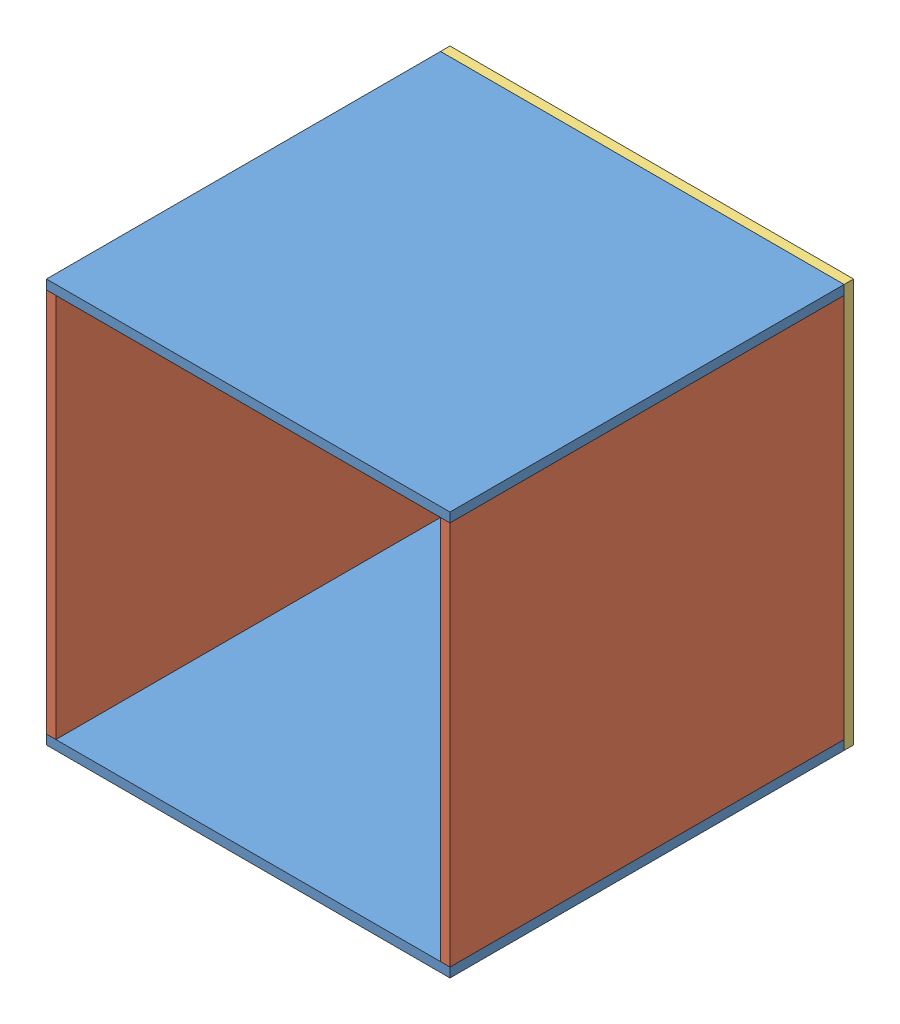
SolidWorks assembly Arm mount box, configuration Default. Lengths in mm.
Overall size (203.2 203.2 203.2).
5 component instances, 3 part files, 12 mates.
Components (placement in the parent):
- Upper Hub top and bottom PL-1: Upper Hub top and bottom PL [Default] at (-17.5452 -93.1073 -0.137) size (203.2 4.76 198.44)
- Upper Hub top and bottom PL-2: Upper Hub top and bottom PL [Default] at (-17.5452 105.3302 -0.137) size (203.2 4.76 198.44)
- Upper Hub side PL-1: Upper Hub side PL [Default] at (84.0548 8.4927 -0.137) x (0 0 1) z (-1 0 0) size (198.44 193.68 4.76)
- Upper Hub side PL-2: Upper Hub side PL [Default] at (-114.3827 8.4927 -0.137) x (0 0 1) z (-1 0 0) size (198.44 193.68 4.76)
- Upper hub PL-1: Upper hub PL [Default] at (-17.5452 8.4927 -104.1182) size (203.2 203.2 4.76)
Mates (geometry in assembly coordinates):
- Coincident11: coincident anti-aligned: plane of Upper Hub side PL-2 through (-119.1452 105.3302 -99.3557) normal (0 0 -1); plane of Upper hub PL-1 through (-119.1452 -93.1073 -99.3557) normal (0 0 1)
- Coincident12: coincident anti-aligned: plane of Upper Hub side PL-1 through (79.2923 110.0927 -99.3557) normal (0 0 -1); plane of Upper hub PL-1 through (-119.1452 -93.1073 -99.3557) normal (0 0 1)
- Coincident14: coincident aligned: plane of Upper Hub side PL-1 through (84.0548 -83.5823 -99.3557) normal (1 0 0); plane of Upper hub PL-1 through (84.0548 110.0927 -99.3557) normal (1 0 0)
- Coincident16: coincident aligned: plane of Upper Hub side PL-2 through (-119.1452 -88.3448 -99.3557) normal (-1 0 0); plane of Upper hub PL-1 through (-119.1452 110.0927 -99.3557) normal (-1 0 0)
- Coincident18: coincident aligned: plane of Upper Hub top and bottom PL-2 through (-119.1452 110.0927 -99.3557) normal (-1 0 0); plane of Upper hub PL-1 through (-119.1452 110.0927 -99.3557) normal (-1 0 0)
- Coincident21: coincident aligned: plane of Upper Hub top and bottom PL-1 through (-119.1452 -88.3448 -99.3557) normal (-1 0 0); plane of Upper Hub side PL-2 through (-119.1452 -88.3448 -99.3557) normal (-1 0 0)
- Coincident23: coincident aligned: plane of Upper Hub top and bottom PL-2 through (84.0548 110.0927 99.0818) normal (0 0 1); plane of Upper Hub side PL-2 through (-119.1452 105.3302 99.0818) normal (0 0 1)
- Coincident24: coincident aligned: plane of Upper Hub top and bottom PL-1 through (84.0548 -88.3448 99.0818) normal (0 0 1); plane of Upper Hub side PL-2 through (-119.1452 105.3302 99.0818) normal (0 0 1)
- Coincident25: coincident aligned: plane of Upper Hub top and bottom PL-1 through (-119.1452 -93.1073 99.0818) normal (0 -1 0); plane of Upper hub PL-1 through (84.0548 -93.1073 -99.3557) normal (0 -1 0)
- Coincident27: coincident aligned: plane of Upper Hub top and bottom PL-2 through (-119.1452 110.0927 99.0818) normal (0 1 0); plane of Upper hub PL-1 through (84.0548 110.0927 -99.3557) normal (0 1 0)
- Coincident28: coincident anti-aligned: plane of Upper Hub top and bottom PL-2 through (-119.1452 105.3302 99.0818) normal (0 -1 0); plane of Upper Hub side PL-2 through (-119.1452 105.3302 99.0818) normal (0 1 0)
- Coincident29: coincident anti-aligned: plane of Upper Hub top and bottom PL-1 through (-119.1452 -88.3448 99.0818) normal (0 1 0); plane of Upper Hub side PL-1 through (79.2923 -88.3448 99.0818) normal (0 -1 0)
